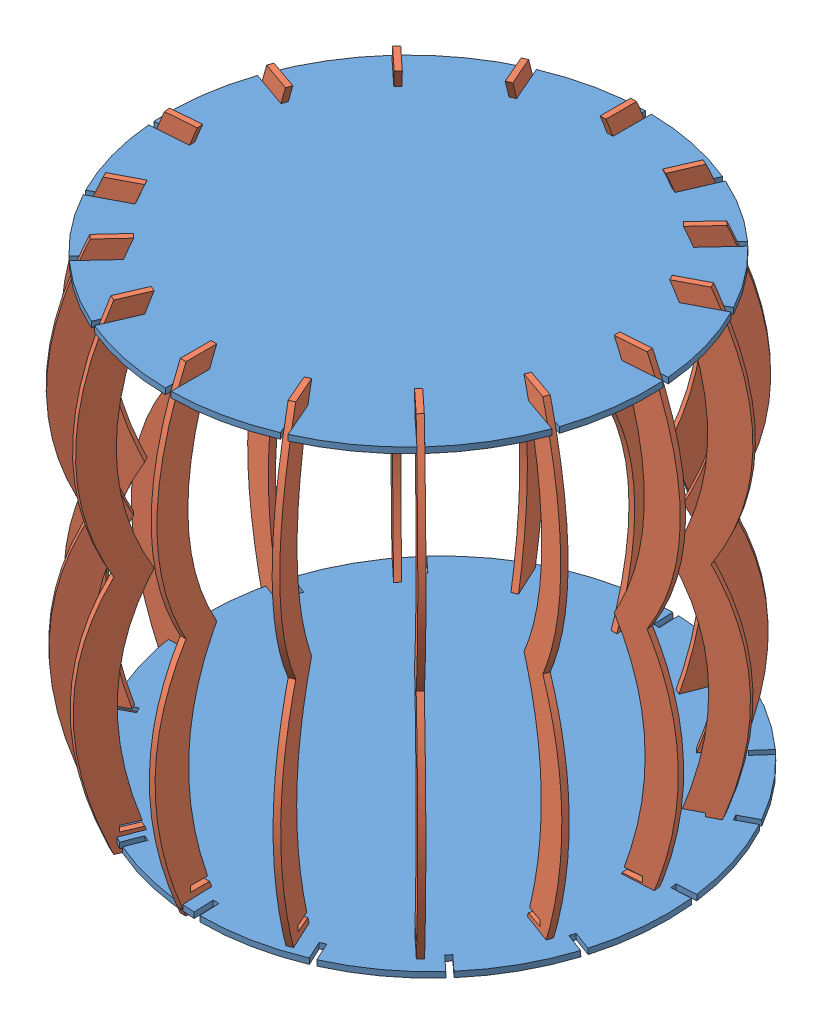
SolidWorks assembly Assem1, configuration Default. Lengths in mm.
Overall size (362.12 250 358.84).
18 component instances, 2 part files, 32 mates.
Components (placement in the parent):
- laserweek2-1: laserweek2 [Default] at (88.8537 253.301 258.3924) x (0.680433 0 -0.73281) z (0.73281 0 0.680433) size (249.98 3 249.98)
- laserweek1-6: laserweek1 [Default] at (127.5926 132.8859 164.8018) x (0.396092 0 -0.918211) z (0 -1 0) size (32.12 3 250)
- laserweek1-8: laserweek1 [Default] at (87.3537 132.8859 157.1123) x (0 0 -1) z (0 -1 0) size (32.12 3 250)
- laserweek1-10: laserweek1 [Default] at (-12.2595 148.8107 264.3933) x (-0.997257 0 0.074021) z (0 1 0) size (32.12 3 250)
- laserweek1-11: laserweek1 [Default] at (156.6688 132.8859 183.1527) x (0.680433 0 -0.73281) z (0 -1 0) size (32.12 3 250)
- laserweek1-12: laserweek1 [Default] at (47.3602 148.8107 350.7947) x (-0.396092 0 0.918211) z (0 1 0) size (32.12 3 250)
- laserweek1-13: laserweek1 [Default] at (49.7538 148.8107 164.952) x (-0.399634 0 -0.916675) z (0 1 0) size (32.12 3 250)
- laserweek1-14: laserweek1 [Default] at (189.7449 132.8859 249.3997) x (0.997257 0 -0.074021) z (0 -1 0) size (32.12 3 250)
- laserweek1-15: laserweek1 [Default] at (-6.2324 148.8107 223.485) x (-0.943741 0 -0.330684) z (0 1 0) size (32.12 3 250)
- laserweek1-16: laserweek1 [Default] at (183.9398 148.8107 293.2997) x (0.943741 0 0.330684) z (0 1 0) size (32.12 3 250)
- laserweek1-17: laserweek1 [Default] at (177.9311 132.8859 210.173) x (0.886373 0 -0.462972) z (0 -1 0) size (32.12 3 250)
- laserweek1-18: laserweek1 [Default] at (87.3537 148.8107 359.6724) x (0 0 1) z (0 1 0) size (32.12 3 250)
- laserweek1-19: laserweek1 [Default] at (21.0386 132.8859 333.632) x (-0.680433 0 0.73281) z (0 -1 0) size (32.12 3 250)
- laserweek1-23: laserweek1 [Default] at (130.7036 132.8859 350.6338) x (0.399634 0 0.916675) z (0 -1 0) size (32.12 3 250)
- laserweek1-26: laserweek1 [Default] at (164.0934 132.8859 326.2075) x (0.73281 0 0.680433) z (0 -1 0) size (32.12 3 250)
- laserweek1-27: laserweek1 [Default] at (-0.2237 132.8859 306.6117) x (-0.886373 0 0.462972) z (0 -1 0) size (32.12 3 250)
- laserweek1-28: laserweek1 [Default] at (13.614 132.8859 190.5772) x (-0.73281 0 -0.680433) z (0 -1 0) size (32.12 3 250)
- laserweek2-3: laserweek2 [Default] at (97.7391 26.7543 252.7919) x (-0.678636 -0.015098 0.73432) z (0.734171 -0.042692 0.677621) size (249.98 3 249.98)
Mates (geometry in assembly coordinates):
- Coincident13: coincident anti-aligned: line of laserweek2-1 through (135.778 256.301 153.4005) axis (-0.918211 0 -0.396092); line of laserweek1-6 through (133.0234 256.301 152.2122) axis (0.918211 0 0.396092)
- Coincident14: coincident aligned: line of laserweek2-1 through (139.7389 256.301 144.2184) axis (-0.396092 0 0.918211); line of laserweek1-6 through (135.778 256.301 153.4005) axis (-0.396092 0 0.918211)
- Coincident18: coincident anti-aligned: plane of laserweek2-1 through (87.3537 256.301 143.4014) normal (0 0 -1); plane of laserweek1-8 through (50.6437 256.301 143.4014) normal (0 0 1)
- Coincident19: coincident anti-aligned: line of laserweek2-1 through (87.3537 256.301 143.4014) axis (0 0 -1); line of laserweek1-8 through (87.3537 256.301 143.4014) axis (0 0 1)
- Coincident21: coincident anti-aligned: plane of laserweek2-1 through (-25.9329 256.301 265.4082) normal (-0.997257 0 0.074021); plane of laserweek1-10 through (-28.6502 256.301 228.7989) normal (0.997257 0 -0.074021)
- Coincident22: coincident anti-aligned: line of laserweek2-1 through (-35.9054 256.301 266.1484) axis (0.997257 0 -0.074021); line of laserweek1-10 through (-16.0278 256.301 264.673) axis (-0.997257 0 0.074021)
- Coincident23: coincident anti-aligned: plane of laserweek2-1 through (165.9982 256.301 173.1052) normal (0.680433 0 -0.73281); plane of laserweek1-11 through (139.0968 256.301 148.1265) normal (-0.680433 0 0.73281)
- Coincident24: coincident aligned: line of laserweek2-1 through (175.001 256.301 167.8184) axis (-0.680433 0 0.73281); line of laserweek1-11 through (168.1966 256.301 175.1465) axis (-0.680433 0 0.73281)
- Coincident25: coincident anti-aligned: plane of laserweek2-1 through (44.684 256.301 364.5725) normal (-0.396092 0 0.918211); plane of laserweek1-12 through (8.2219 256.301 348.8437) normal (0.396092 0 -0.918211)
- Coincident26: coincident anti-aligned: line of laserweek2-1 through (37.9685 256.301 372.5663) axis (0.396092 0 -0.918211); line of laserweek1-12 through (45.8635 256.301 354.2642) axis (-0.396092 0 0.918211)
- Coincident27: coincident anti-aligned: plane of laserweek2-1 through (41.5244 256.301 153.5824) normal (-0.399634 0 -0.916675); plane of laserweek1-13 through (77.9256 256.301 137.713) normal (0.399634 0 0.916675)
- Coincident28: coincident aligned: line of laserweek2-1 through (41.5244 256.301 153.5824) axis (-0.399634 0 -0.916675); line of laserweek1-13 through (45.4937 256.301 162.6872) axis (-0.399634 0 -0.916675)
- Coincident29: coincident anti-aligned: plane of laserweek2-1 through (203.6403 256.301 251.3765) normal (0.997257 0 -0.074021); plane of laserweek1-14 through (200.7009 256.301 211.7755) normal (-0.997257 0 0.074021)
- Coincident30: coincident aligned: line of laserweek2-1 through (213.6128 256.301 250.6363) axis (-0.997257 0 0.074021); line of laserweek1-14 through (203.6403 256.301 251.3765) axis (-0.997257 0 0.074021)
- Coincident31: coincident anti-aligned: plane of laserweek2-1 through (-19.172 256.301 218.951) normal (-0.943741 0 -0.330684); plane of laserweek1-15 through (-7.0326 256.301 184.3063) normal (0.943741 0 0.330684)
- Coincident32: coincident aligned: line of laserweek2-1 through (-20.1641 256.301 221.7823) axis (-0.943741 0 -0.330684); line of laserweek1-15 through (-10.7905 256.301 225.0667) axis (-0.943741 0 -0.330684)
- Coincident33: coincident anti-aligned: plane of laserweek2-1 through (196.8794 256.301 297.8337) normal (0.943741 0 0.330684); plane of laserweek1-16 through (184.74 256.301 332.4784) normal (-0.943741 0 -0.330684)
- Coincident34: coincident anti-aligned: line of laserweek2-1 through (206.3169 256.301 301.1405) axis (-0.943741 0 -0.330684); line of laserweek1-16 through (187.5059 256.301 294.5492) axis (0.943741 0 0.330684)
- Coincident35: coincident anti-aligned: plane of laserweek2-1 through (191.4731 256.301 206.4843) normal (0.886373 0 -0.462972); plane of laserweek1-17 through (173.0885 256.301 171.2865) normal (-0.886373 0 0.462972)
- Coincident36: coincident aligned: line of laserweek2-1 through (190.0842 253.301 203.8252) axis (0.886373 0 -0.462972); line of laserweek1-17 through (182.1648 253.301 207.9617) axis (0.886373 0 -0.462972)
- Coincident37: coincident anti-aligned: plane of laserweek2-1 through (90.3537 256.301 373.3834) normal (0 0 1); plane of laserweek1-18 through (50.6437 256.301 373.3834) normal (0 0 -1)
- Coincident38: coincident aligned: line of laserweek2-1 through (90.3537 256.301 373.3834) axis (0 0 1); line of laserweek1-18 through (90.3537 256.301 363.451) axis (0 0 1)
- Coincident41: coincident anti-aligned: plane of laserweek2-1 through (9.5108 256.301 341.6383) normal (-0.680433 0 0.73281); plane of laserweek1-19 through (38.6106 256.301 368.6583) normal (0.680433 0 -0.73281)
- Coincident42: coincident aligned: line of laserweek2-1 through (2.7064 256.301 348.9664) axis (0.680433 0 -0.73281); line of laserweek1-19 through (9.5108 256.301 341.6383) axis (0.680433 0 -0.73281)
- Coincident45: coincident anti-aligned: plane of laserweek2-1 through (136.183 256.301 363.2023) normal (0.399634 0 0.916675); plane of laserweek1-23 through (169.8341 256.301 348.5317) normal (-0.399634 0 -0.916675)
- Coincident46: coincident anti-aligned: line of laserweek2-1 through (136.183 256.301 363.2023) axis (0.399634 0 0.916675); line of laserweek1-23 through (136.183 256.301 363.2023) axis (-0.399634 0 -0.916675)
- Coincident48: coincident anti-aligned: plane of laserweek2-1 through (172.0996 256.301 337.7353) normal (0.73281 0 0.680433); plane of laserweek1-26 through (199.1196 256.301 308.6354) normal (-0.73281 0 -0.680433)
- Coincident49: coincident aligned: line of laserweek2-1 through (179.4277 256.301 344.5396) axis (-0.73281 0 -0.680433); line of laserweek1-26 through (172.0996 256.301 337.7353) axis (-0.73281 0 -0.680433)
- Coincident50: coincident anti-aligned: plane of laserweek2-1 through (-13.7657 256.301 310.3004) normal (-0.886373 0 0.462972); plane of laserweek1-27 through (4.6189 256.301 345.4983) normal (0.886373 0 -0.462972)
- Coincident51: coincident aligned: line of laserweek2-1 through (-22.6294 256.301 314.9301) axis (0.886373 0 -0.462972); line of laserweek1-27 through (-13.7657 256.301 310.3004) axis (0.886373 0 -0.462972)
- Coincident52: coincident anti-aligned: plane of laserweek2-1 through (3.5665 256.301 181.2479) normal (-0.73281 0 -0.680433); plane of laserweek1-28 through (-21.4122 256.301 208.1493) normal (0.73281 0 0.680433)
- Coincident53: coincident anti-aligned: line of laserweek2-1 through (3.5665 256.301 181.2479) axis (-0.73281 0 -0.680433); line of laserweek1-28 through (3.5665 256.301 181.2479) axis (0.73281 0 0.680433)
